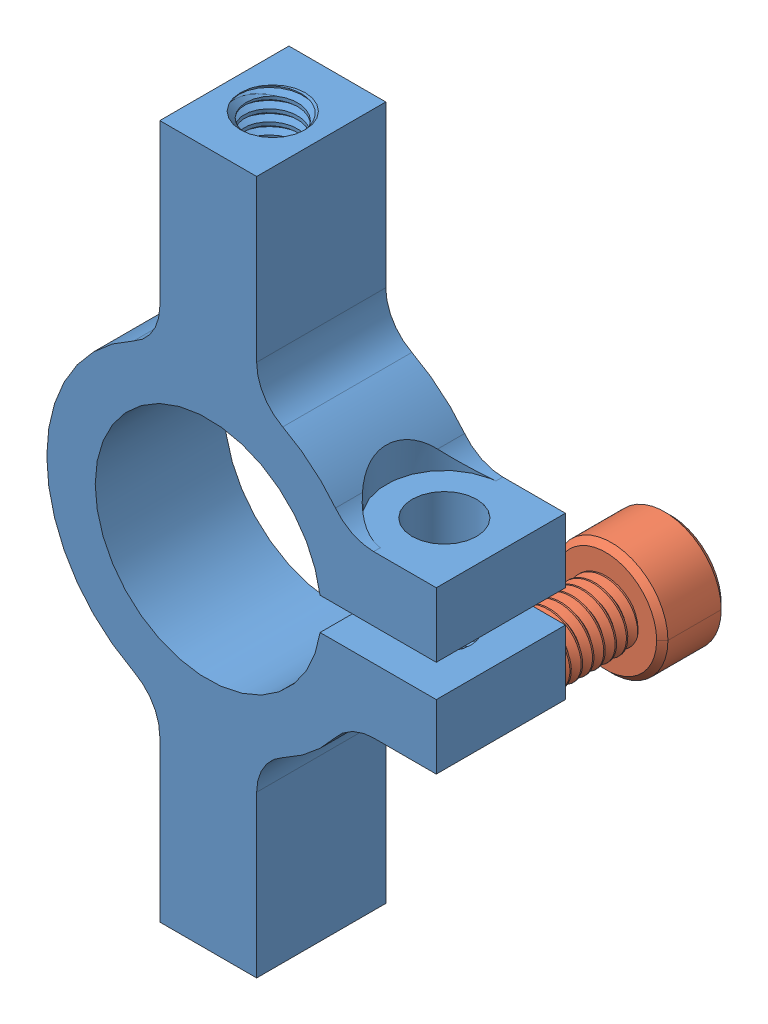
SolidWorks assembly 1402-0043-0014, configuration Default. Lengths in mm.
Overall size (24.13 43.01 18.01).
3 component instances, 2 part files, 0 mates.
Components (placement in the parent):
- 1402-0043-0014.step-1: 1402-0043-0014.step [Default] at origin size (24.13 43.01 18.01)
  - 1402-0043-0014 without hardware.step-1: 1402-0043-0014 without hardware.step [Default] at (-10.2331 3.9775 4.6446) x (0 -1 0) z (1 0 0) size (43.01 8 24.13)
  - 2800-0004-0010.step-1: 2800-0004-0010.step [Default] at (0.3951 -1.0225 8.6446) size (7 7 14.01)
